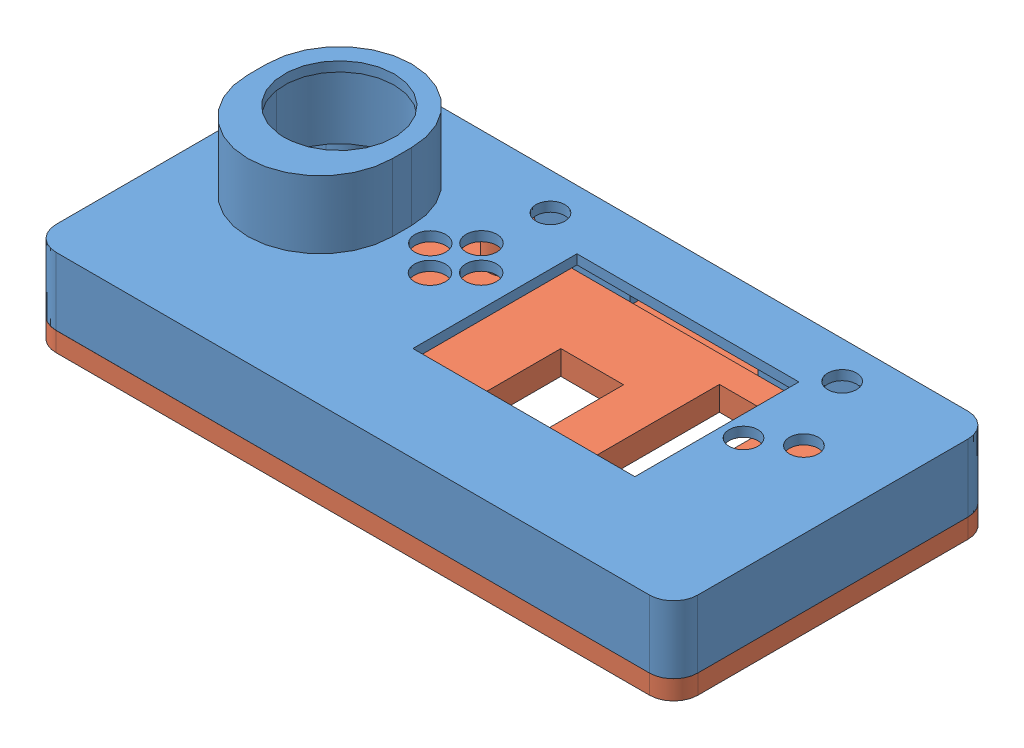
SolidWorks assembly 어셈블리1, configuration 기본. Lengths in mm.
Overall size (133 32 66.02).
2 component instances, 2 part files, 3 mates.
Components (placement in the parent):
- Part-1-1: Part-1 [기본] at (-13.1354 -7.1852 166) size (133 28 66.02)
- Part-2-1: Part-2 [기본] at (-13.1328 -12.1852 166) size (133 12.3 66.02)
Mates (geometry in assembly coordinates):
- 동심1: concentric: cylinder of Part-1-1 through (-73.5755 3.8148 159.9079) axis (0 -1 0) radius 1.25; cylinder of Part-2-1 through (-73.5755 -14.4852 159.9079) axis (0 1 0) radius 1.5
- 동심2: concentric: cylinder of Part-1-1 through (47.3073 3.8148 106.0712) axis (0 -1 0) radius 1.25; cylinder of Part-2-1 through (47.3073 -14.4852 106.0712) axis (0 1 0) radius 1.5
- 일치1: coincident anti-aligned: plane of Part-1-1 through (-74.6346 -7.1852 104.9895) normal (0 -1 0); plane of Part-2-1 through (48.3664 -7.1852 104.9895) normal (0 1 0)
